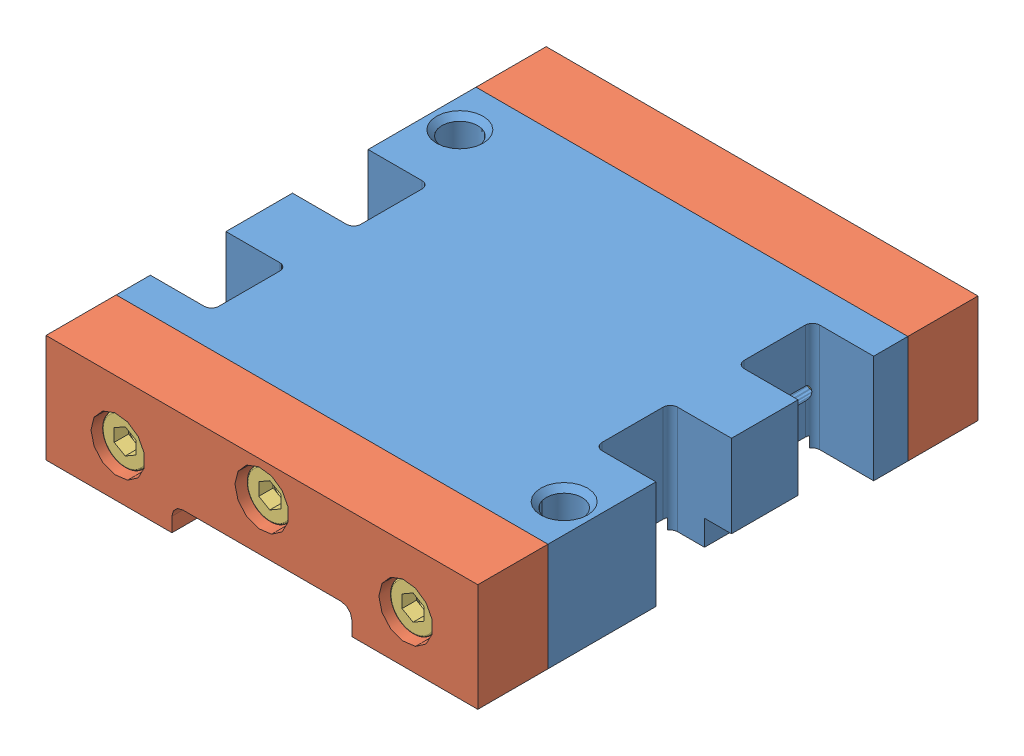
SolidWorks assembly ЧМВ1.03.00 - Сборка пуансона , configuration По умолчанию. Lengths in mm.
Overall size (120 30 139).
9 component instances, 3 part files, 14 mates.
Components (placement in the parent):
- ЧМВ1.03.02 -Пуансон-2: ЧМВ1.03.02 -Пуансон [Default] at (84.7865 149.5092 243.5787) size (120 30 100)
- ЧМВ1.03.01 - Боковина пуансона-3: ЧМВ1.03.01 - Боковина пуансона [Default] at (84.7865 164.5092 193.5787) x (1 0 0) z (0 0 -1) size (120 30 19.5)
- ЧМВ1.03.01 - Боковина пуансона-4: ЧМВ1.03.01 - Боковина пуансона [Default] at (84.7865 164.5092 293.5787) x (-1 0 0) z (0 0 1) size (120 30 19.5)
- socket head cap screw_iso-1: socket head cap screw_iso [ISO 4762 M8 x 16 - 16N] at (44.7865 163.0092 311.0787) x (0 0 -1) z (1 0 0) size (24 13 13)
- socket head cap screw_iso-2: socket head cap screw_iso [ISO 4762 M8 x 16 - 16N] at (124.7865 163.0092 311.0787) x (0 0 -1) z (1 0 0) size (24 13 13)
- socket head cap screw_iso-3: socket head cap screw_iso [ISO 4762 M8 x 16 - 16N] at (85.1489 170.29 311.2498) x (0 0 -1) z (1 0 0) size (24 13 13)
- socket head cap screw_iso-4: socket head cap screw_iso [ISO 4762 M8 x 16 - 16N] at (124.7865 163.0092 176.0787) x (0 0 1) z (-1 0 0) size (24 13 13)
- socket head cap screw_iso-5: socket head cap screw_iso [ISO 4762 M8 x 16 - 16N] at (84.7865 170.0092 176.0787) x (0 0 1) z (-1 0 0) size (24 13 13)
- socket head cap screw_iso-6: socket head cap screw_iso [ISO 4762 M8 x 16 - 16N] at (44.7865 163.0092 176.0787) x (0 0 1) z (-1 0 0) size (24 13 13)
Mates (geometry in assembly coordinates):
- Совпадение1: coincident anti-aligned: plane of Пуансон-2 through (144.7865 179.5092 293.5787) normal (0 0 1); plane of Боковина пуансона-4 through (84.7865 164.5092 293.5787) normal (0 0 -1)
- Совпадение2: coincident anti-aligned: plane of Пуансон-2 through (144.7865 179.5092 193.5787) normal (0 0 -1); plane of Боковина пуансона-3 through (84.7865 164.5092 193.5787) normal (0 0 1)
- Концентричный3: concentric anti-aligned: cylinder of Пуансон-2 through (44.7865 163.0092 293.5787) axis (0 0 1) radius 3.5; cylinder of Боковина пуансона-4 through (44.7865 163.0092 313.0787) axis (0 0 -1) radius 4.5
- Концентричный4: concentric anti-aligned: cylinder of Пуансон-2 through (124.7865 163.0092 293.5787) axis (0 0 1) radius 3.5; cylinder of Боковина пуансона-4 through (124.7865 163.0092 313.0787) axis (0 0 -1) radius 4.5
- Концентричный5: concentric aligned: cylinder of Боковина пуансона-4 through (44.7865 163.0092 303.0787) axis (0 0 1) radius 7.5; cylinder of socket head cap screw_iso-1 through (44.7865 163.0092 342.8287) axis (0 0 1) radius 6.5
- Совпадение3: coincident anti-aligned: plane of Боковина пуансона-4 through (44.7865 163.0092 303.0787) normal (0 0 1); plane of socket head cap screw_iso-1 through (44.7865 169.5092 303.0787) normal (0 0 -1)
- Концентричный6: concentric anti-aligned: cylinder of Боковина пуансона-4 through (124.7865 163.0092 313.0787) axis (0 0 -1) radius 4.5; cylinder of socket head cap screw_iso-2 through (124.7865 163.0092 342.8287) axis (0 0 1) radius 6.5
- Совпадение4: coincident anti-aligned: plane of Боковина пуансона-4 through (124.7865 163.0092 303.0787) normal (0 0 1); plane of socket head cap screw_iso-2 through (124.7865 169.5092 303.0787) normal (0 0 -1)
- Концентричный7: concentric anti-aligned: cylinder of Боковина пуансона-3 through (124.7865 163.0092 174.0787) axis (0 0 1) radius 4.5; cylinder of socket head cap screw_iso-4 through (124.7865 163.0092 144.3287) axis (0 0 -1) radius 6.5
- Совпадение5: coincident anti-aligned: plane of Боковина пуансона-3 through (124.7865 163.0092 184.0787) normal (0 0 -1); plane of socket head cap screw_iso-4 through (124.7865 169.5092 184.0787) normal (0 0 1)
- Концентричный8: concentric anti-aligned: cylinder of Боковина пуансона-3 through (84.7865 170.0092 174.0787) axis (0 0 1) radius 4.5; cylinder of socket head cap screw_iso-5 through (84.7865 170.0092 144.3287) axis (0 0 -1) radius 6.5
- Совпадение6: coincident anti-aligned: plane of Боковина пуансона-3 through (84.7865 170.0092 184.0787) normal (0 0 -1); plane of socket head cap screw_iso-5 through (84.7865 176.5092 184.0787) normal (0 0 1)
- Концентричный9: concentric aligned: cylinder of Боковина пуансона-3 through (44.7865 163.0092 184.0787) axis (0 0 -1) radius 7.5; cylinder of socket head cap screw_iso-6 through (44.7865 163.0092 144.3287) axis (0 0 -1) radius 6.5
- Совпадение7: coincident anti-aligned: plane of Боковина пуансона-3 through (44.7865 163.0092 184.0787) normal (0 0 -1); plane of socket head cap screw_iso-6 through (44.7865 169.5092 184.0787) normal (0 0 1)
